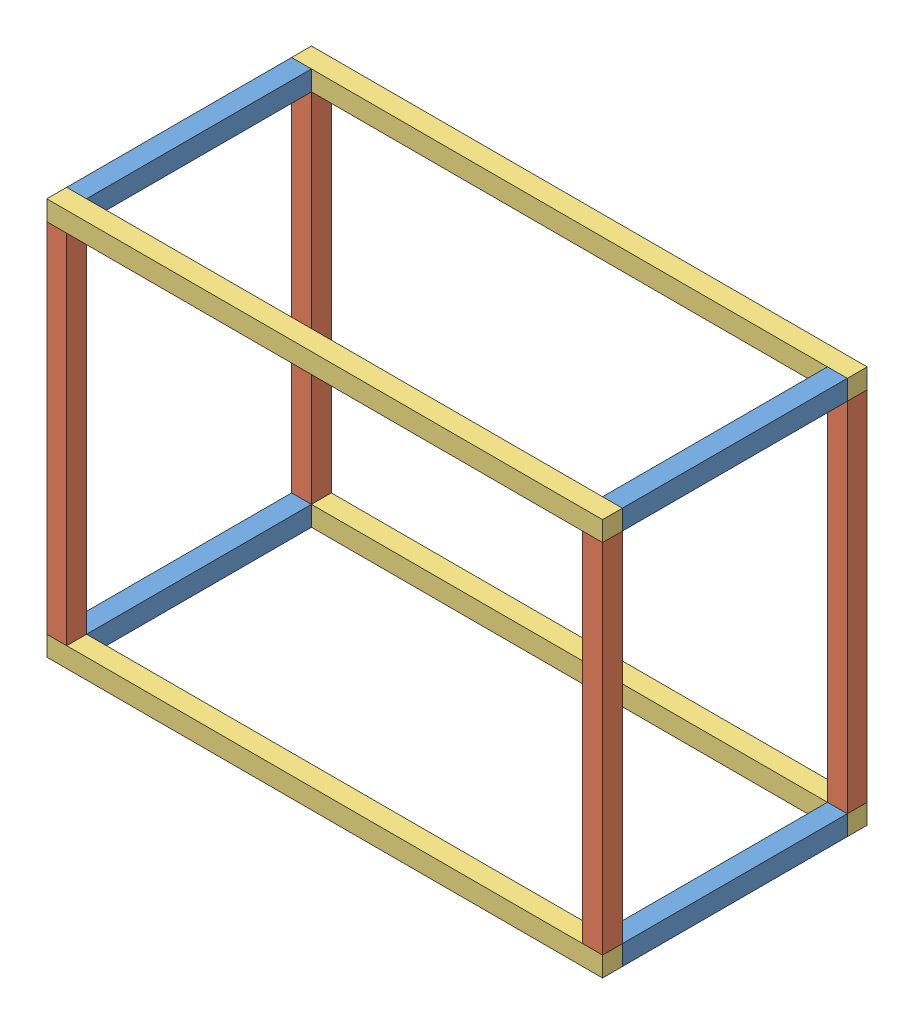
SolidWorks assembly Assemblage Panier, configuration Défaut. Lengths in mm.
Overall size (420 300 200).
12 component instances, 3 part files, 33 mates.
Components (placement in the parent):
- profilé 170x15x15-1: profilé 170x15x15 [Défaut] at (-3.3117 -1.6501 75) size (15 15 170)
- profilé 270x15x15-1: profilé 270x15x15 [Défaut] at (-3.3117 5.8499 252.5) x (1 0 0) z (0 1 0) size (15 15 270)
- profilé 420x15x15-1: profilé 420x15x15 [Défaut] at (409.1883 -1.6501 252.5) x (0 0 1) z (-1 0 0) size (15 15 420)
- profilé 170x15x15-2: profilé 170x15x15 [Défaut] at (401.6883 -1.6501 75) size (15 15 170)
- profilé 270x15x15-2: profilé 270x15x15 [Défaut] at (-3.3117 275.8499 67.5) x (1 0 0) z (0 -1 0) size (15 15 270)
- profilé 420x15x15-2: profilé 420x15x15 [Défaut] at (409.1883 -1.6501 67.5) x (0 0 1) z (-1 0 0) size (15 15 420)
- profilé 170x15x15-3: profilé 170x15x15 [Défaut] at (-3.3117 283.3499 75) size (15 15 170)
- profilé 270x15x15-3: profilé 270x15x15 [Défaut] at (401.6883 5.8499 252.5) x (1 0 0) z (0 1 0) size (15 15 270)
- profilé 420x15x15-3: profilé 420x15x15 [Défaut] at (-10.8117 283.3499 252.5) x (0 0 -1) z (1 0 0) size (15 15 420)
- profilé 170x15x15-4: profilé 170x15x15 [Défaut] at (401.6883 283.3499 75) size (15 15 170)
- profilé 270x15x15-4: profilé 270x15x15 [Défaut] at (401.6883 275.8499 67.5) x (1 0 0) z (0 -1 0) size (15 15 270)
- profilé 420x15x15-4: profilé 420x15x15 [Défaut] at (409.1883 283.3499 67.5) x (0 0 1) z (-1 0 0) size (15 15 420)
Mates (geometry in assembly coordinates):
- Parallèle1: parallel anti-aligned: plane of profilé 150x25x25-1 through (-3.3117 -1.6501 245) normal (0 0 1); plane of profilé 420x25x25-1 through (-10.8117 -9.1501 245) normal (0 0 -1)
- Coïncidente2: coincident aligned: line of profilé 150x25x25-1 through (-10.8117 5.8499 245) axis (0 -1 0); line of profilé 420x25x25-1 through (-10.8117 5.8499 245) axis (0 -1 0)
- Coïncidente3: coincident anti-aligned: line of profilé 150x25x25-1 through (4.1883 5.8499 245) axis (-1 0 0); line of profilé 420x25x25-1 through (-10.8117 5.8499 245) axis (1 0 0)
- Parallèle2: parallel anti-aligned: plane of profilé 250x25x25-1 through (-3.3117 5.8499 252.5) normal (0 -1 0); plane of profilé 420x25x25-1 through (-10.8117 5.8499 245) normal (0 1 0)
- Coïncidente5: coincident anti-aligned: line of profilé 250x25x25-1 through (-10.8117 5.8499 245) axis (0 0 1); line of profilé 420x25x25-1 through (-10.8117 5.8499 260) axis (0 0 -1)
- Coïncidente6: coincident aligned: line of profilé 250x25x25-1 through (-10.8117 5.8499 260) axis (1 0 0); line of profilé 420x25x25-1 through (-10.8117 5.8499 260) axis (1 0 0)
- Parallèle4: parallel anti-aligned: plane of profilé 150x25x25-1 through (-3.3117 -1.6501 75) normal (0 0 -1); plane of profilé 420x25x25-2 through (-10.8117 -9.1501 75) normal (0 0 1)
- Coïncidente9: coincident anti-aligned: line of profilé 150x25x25-1 through (-10.8117 5.8499 75) axis (0 -1 0); line of profilé 420x25x25-2 through (-10.8117 -9.1501 75) axis (0 1 0)
- Coïncidente10: coincident anti-aligned: line of profilé 150x25x25-1 through (4.1883 5.8499 75) axis (-1 0 0); line of profilé 420x25x25-2 through (-10.8117 5.8499 75) axis (1 0 0)
- Parallèle5: parallel anti-aligned: plane of profilé 150x25x25-2 through (401.6883 -1.6501 75) normal (0 0 -1); plane of profilé 420x25x25-2 through (-10.8117 -9.1501 75) normal (0 0 1)
- Coïncidente12: coincident anti-aligned: line of profilé 420x25x25-1 through (-10.8117 5.8499 245) axis (1 0 0); line of profilé 150x25x25-2 through (409.1883 5.8499 245) axis (-1 0 0)
- Coïncidente13: coincident anti-aligned: line of profilé 420x25x25-1 through (409.1883 5.8499 245) axis (0 -1 0); line of profilé 150x25x25-2 through (409.1883 -9.1501 245) axis (0 1 0)
- Parallèle6: parallel anti-aligned: plane of profilé 250x25x25-2 through (-3.3117 5.8499 67.5) normal (0 -1 0); plane of profilé 420x25x25-2 through (-10.8117 5.8499 60) normal (0 1 0)
- Coïncidente15: coincident anti-aligned: line of profilé 250x25x25-2 through (4.1883 5.8499 75) axis (-1 0 0); line of profilé 420x25x25-2 through (-10.8117 5.8499 75) axis (1 0 0)
- Coïncidente16: coincident aligned: line of profilé 250x25x25-2 through (-10.8117 5.8499 75) axis (0 0 -1); line of profilé 420x25x25-2 through (-10.8117 5.8499 75) axis (0 0 -1)
- Parallèle8: parallel anti-aligned: plane of profilé 420x25x25-1 through (-10.8117 5.8499 245) normal (0 1 0); plane of profilé 250x25x25-3 through (401.6883 5.8499 252.5) normal (0 -1 0)
- Coïncidente21: coincident anti-aligned: line of profilé 420x25x25-1 through (-10.8117 5.8499 245) axis (1 0 0); line of profilé 250x25x25-3 through (409.1883 5.8499 245) axis (-1 0 0)
- Coïncidente22: coincident aligned: line of profilé 420x25x25-1 through (409.1883 5.8499 260) axis (0 0 -1); line of profilé 250x25x25-3 through (409.1883 5.8499 260) axis (0 0 -1)
- Parallèle11: parallel anti-aligned: plane of profilé 250x25x25-1 through (-3.3117 275.8499 252.5) normal (0 1 0); plane of profilé 420x25x25-3 through (409.1883 275.8499 260) normal (0 -1 0)
- Coïncidente31: coincident aligned: line of profilé 250x25x25-3 through (409.1883 275.8499 260) axis (0 0 -1); line of profilé 420x25x25-3 through (409.1883 275.8499 260) axis (0 0 -1)
- Coïncidente32: coincident anti-aligned: line of profilé 250x25x25-3 through (394.1883 275.8499 260) axis (1 0 0); line of profilé 420x25x25-3 through (409.1883 275.8499 260) axis (-1 0 0)
- Parallèle12: parallel anti-aligned: plane of profilé 420x25x25-2 through (-10.8117 5.8499 60) normal (0 1 0); plane of profilé 250x25x25-4 through (401.6883 5.8499 67.5) normal (0 -1 0)
- Coïncidente34: coincident anti-aligned: line of profilé 420x25x25-2 through (-10.8117 5.8499 75) axis (1 0 0); line of profilé 250x25x25-4 through (409.1883 5.8499 75) axis (-1 0 0)
- Coïncidente35: coincident anti-aligned: line of profilé 420x25x25-2 through (409.1883 5.8499 75) axis (0 0 -1); line of profilé 250x25x25-4 through (409.1883 5.8499 60) axis (0 0 1)
- Parallèle13: parallel anti-aligned: plane of profilé 150x25x25-4 through (394.1883 275.8499 245) normal (0 -1 0); plane of profilé 250x25x25-4 through (401.6883 275.8499 67.5) normal (0 1 0)
- Coïncidente39: coincident anti-aligned: line of profilé 150x25x25-4 through (394.1883 275.8499 75) axis (1 0 0); line of profilé 250x25x25-4 through (409.1883 275.8499 75) axis (-1 0 0)
- Coïncidente40: coincident aligned: line of profilé 420x25x25-3 through (409.1883 275.8499 245) axis (0 1 0); line of profilé 150x25x25-4 through (409.1883 275.8499 245) axis (0 1 0)
- Parallèle14: parallel anti-aligned: plane of profilé 250x25x25-4 through (401.6883 275.8499 67.5) normal (0 1 0); plane of profilé 420x25x25-4 through (-10.8117 275.8499 60) normal (0 -1 0)
- Coïncidente42: coincident anti-aligned: line of profilé 250x25x25-2 through (-10.8117 275.8499 75) axis (0 0 -1); line of profilé 420x25x25-4 through (-10.8117 275.8499 60) axis (0 0 1)
- Coïncidente43: coincident aligned: line of profilé 250x25x25-2 through (-10.8117 275.8499 60) axis (1 0 0); line of profilé 420x25x25-4 through (-10.8117 275.8499 60) axis (1 0 0)
- Parallèle15: parallel anti-aligned: plane of profilé 150x25x25-3 through (-3.3117 283.3499 245) normal (0 0 1); plane of profilé 420x25x25-3 through (409.1883 275.8499 245) normal (0 0 -1)
- Coïncidente46: coincident anti-aligned: line of profilé 150x25x25-3 through (4.1883 290.8499 75) axis (-1 0 0); line of profilé 420x25x25-4 through (-10.8117 290.8499 75) axis (1 0 0)
- Coïncidente47: coincident anti-aligned: line of profilé 150x25x25-3 through (-10.8117 290.8499 245) axis (0 -1 0); line of profilé 420x25x25-3 through (-10.8117 275.8499 245) axis (0 1 0)
